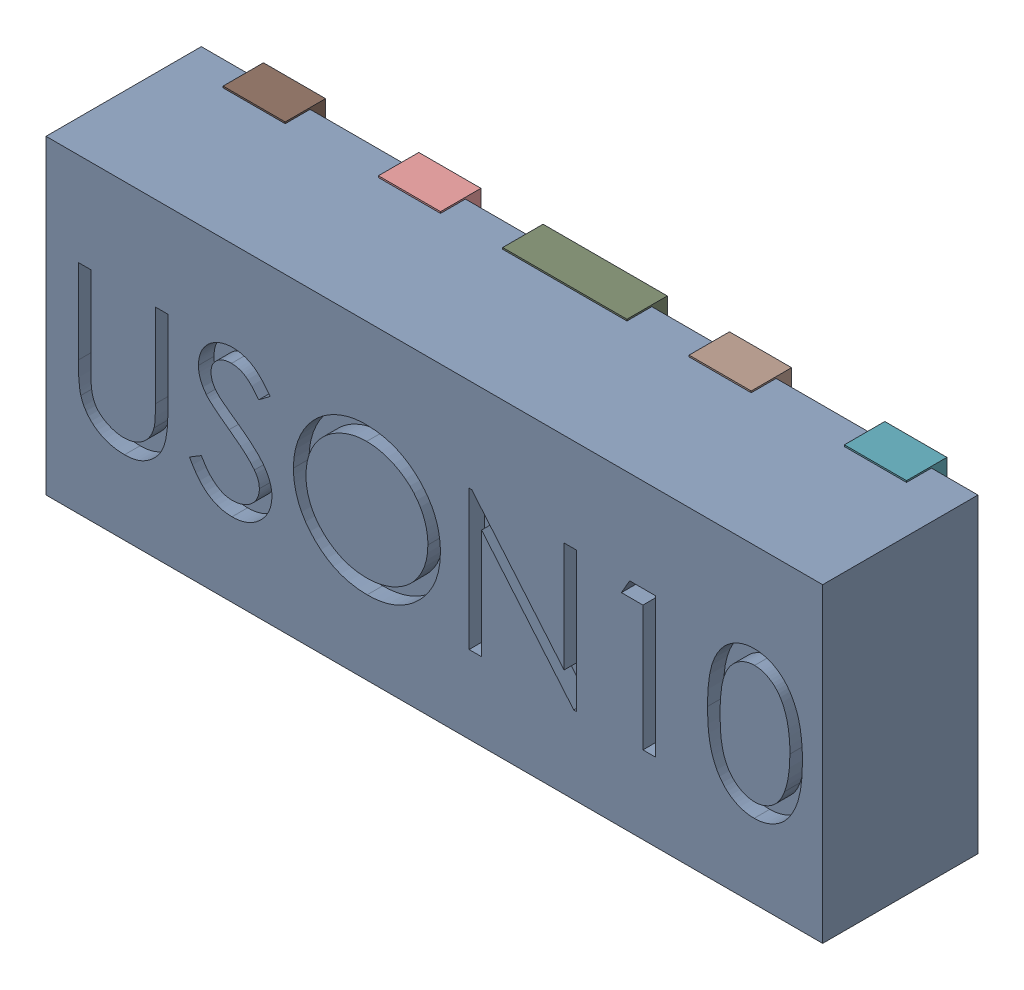
SolidWorks assembly D4, configuration Défaut. Lengths in mm.
Overall size (2.5 1.01 0.55).
12 component instances, 5 part files, 0 mates.
Components (placement in the parent):
- UDFN10-1: UDFN10 [Défaut] at (57.7173 -26.8269 -0.9099) x (1 0 0) z (0 -1 0) size (2.5 0.55 1.01)
  - User Library-UDFN10_Body-1: User Library-UDFN10_Body [Défaut] at (1.0785 0.9721 1.8983) size (2.5 0.5 1)
  - User Library-UDFN10_Pin1-1: User Library-UDFN10_Pin1 [Défaut] at (0.0785 1.0521 2.2208) x (0 0 -1) z (-1 0 0) size (0.37 0.13 0.2)
  - User Library-UDFN10_Pin2-1: User Library-UDFN10_Pin2 [Défaut] at (0.5785 1.0521 2.2208) x (0 0 1) z (1 0 0) size (0.37 0.13 0.2)
  - User Library-UDFN10_Pin4-1: User Library-UDFN10_Pin4 [Défaut] at (1.0785 0.9221 2.2208) x (0 0 1) z (-1 0 0) size (0.49 0.13 0.4)
  - User Library-UDFN10_Pin2-2: User Library-UDFN10_Pin2 [Défaut] at (1.5785 0.9221 2.2208) x (0 0 1) z (-1 0 0) size (0.37 0.13 0.2)
  - User Library-UDFN10_Pin2-3: User Library-UDFN10_Pin2 [Défaut] at (2.0785 0.9221 2.2208) x (0 0 1) z (-1 0 0) size (0.37 0.13 0.2)
  - User Library-UDFN10_Pin2-4: User Library-UDFN10_Pin2 [Défaut] at (2.0785 0.9221 1.5758) x (0 0 -1) z (1 0 0) size (0.37 0.13 0.2)
  - User Library-UDFN10_Pin2-5: User Library-UDFN10_Pin2 [Défaut] at (1.5785 0.9221 1.5758) x (0 0 -1) z (1 0 0) size (0.37 0.13 0.2)
  - User Library-UDFN10_Pin3-1: User Library-UDFN10_Pin3 [Défaut] at (1.0785 0.9221 1.5758) x (0 0 1) z (-1 0 0) size (0.37 0.13 0.4)
  - User Library-UDFN10_Pin2-6: User Library-UDFN10_Pin2 [Défaut] at (0.5785 0.9221 1.5758) x (0 0 -1) z (1 0 0) size (0.37 0.13 0.2)
  - User Library-UDFN10_Pin2-7: User Library-UDFN10_Pin2 [Défaut] at (0.0785 0.9221 1.5758) x (0 0 -1) z (1 0 0) size (0.37 0.13 0.2)
